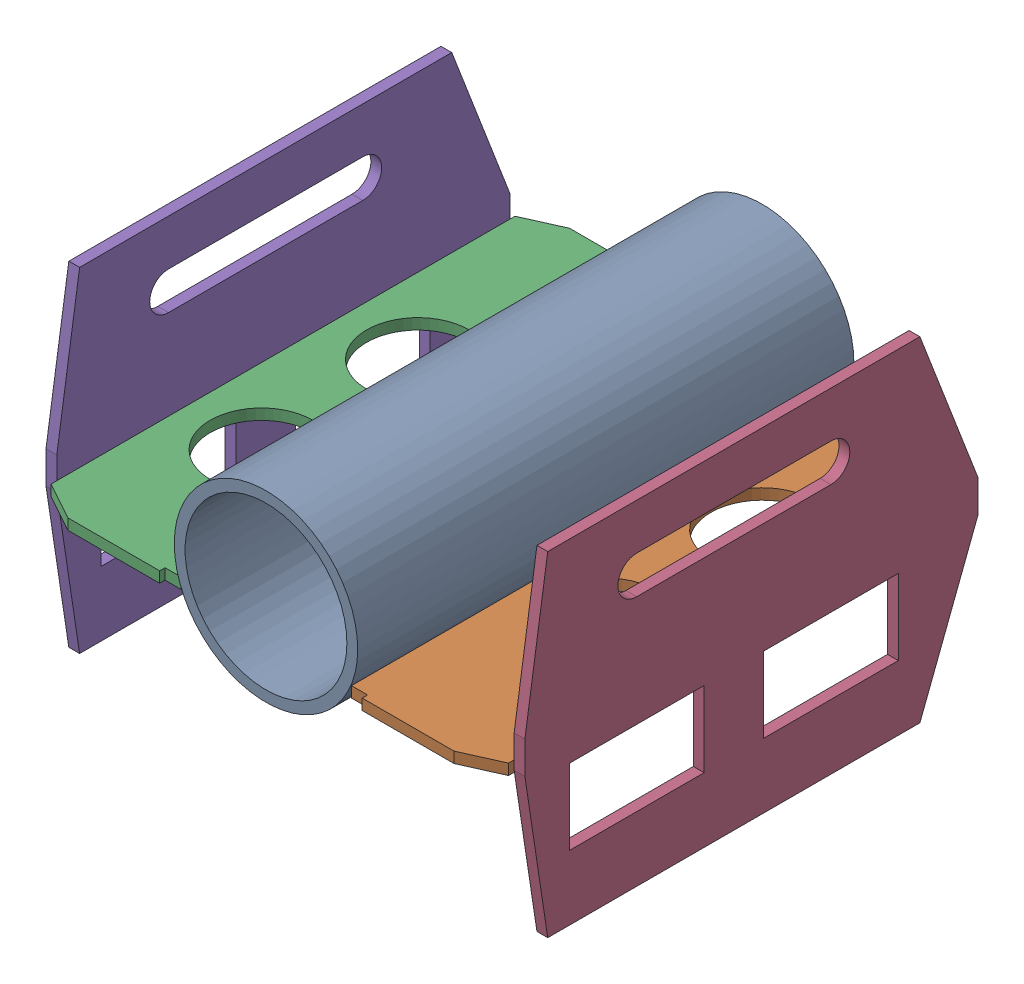
SolidWorks assembly Assembled UUV 1.0, configuration Default. Lengths in mm.
Overall size (450.07 315.04 466.6).
5 component instances, 3 part files, 0 mates.
Components (placement in the parent):
- Central Pipe 1.0-1: Central Pipe 1.0 [Default] at origin size (170 170 460)
- Side Flaps 1.0-1: Side Flaps 1.0 [Default] at (213.3041 -32.8736 448.4493) x (0 0 1) z (0 -1 0) size (465 135 10)
- Side Flaps 1.0-2: Side Flaps 1.0 [Default] at (-216.0676 -26.166 13.1222) x (0 0 -1) z (0 -1 0) size (465 135 10)
- Side Wings 1.0-1: Side Wings 1.0 [Default] at (213.3769 -181.1239 77.2118) x (0 0 -1) z (1 0 0) size (420 310 10)
- Side Wings 1.0-2: Side Wings 1.0 [Default] at (-226.6895 -176.0852 71.0908) x (0 0 -1) z (1 0 0) size (420 310 10)
